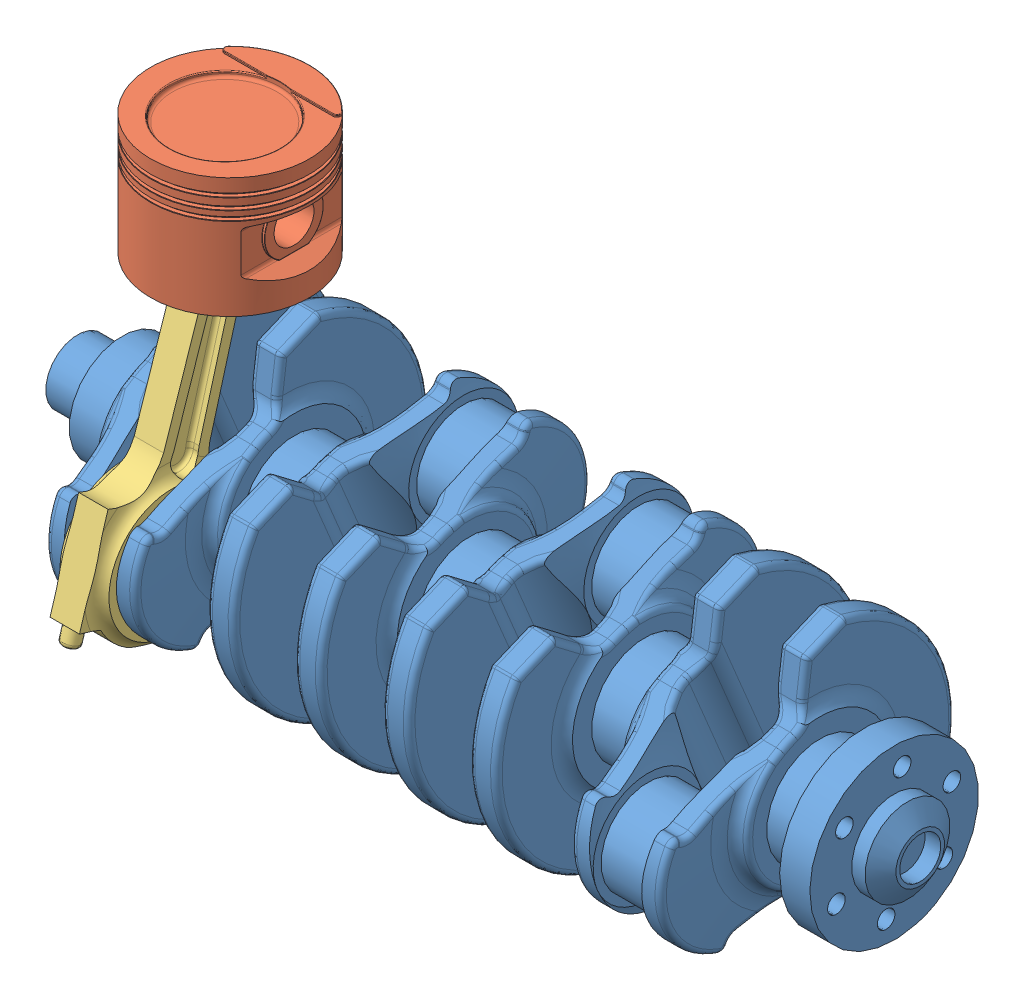
SolidWorks assembly Engine, configuration Default. Lengths in mm.
Overall size (462.5 296.54 181.27).
4 component instances, 3 part files, 4 mates.
Components (placement in the parent):
- Crankshaft-1: Crankshaft [Default] at (-1.3622 0 0) x (1 0 0) z (0 0.922873 0.385104) size (429.6 147.6 117)
- piston_rod-1: piston_rod [Default] at (29.6993 121.1932 0) size (81 215.94 127.72) (flexible)
  - Piston-1: Piston [Default] at (1.4385 31.8218 0) size (81 62.3 81)
  - ConRod-1: ConRod [Default] at (12.4385 -0.1282 0) x (0 0.291501 0.956571) z (-1 0 0) size (72.5 196.5 26.37)
Mates (geometry in assembly coordinates):
- Concentrico1: concentric aligned: cylinder of Crankshaft-1 through (-46.5622 0 0) axis (1 0 0) radius 16.3; line of assembly
- Concentrico2: concentric aligned: cylinder of Crankshaft-1 through (111.8201 -17.6378 42.2676) axis (-1 0 0) radius 24; cylinder of piston_rod-1/ConRod-1 through (41.6378 -17.6378 42.2676) axis (-1 0 0) radius 24
- Coincidente2: coincident anti-aligned: plane of Crankshaft-1 through (18.6378 0 0) normal (1 0 0); plane of piston_rod-1/ConRod-1 through (18.6378 -17.6378 42.2676) normal (-1 0 0)
- Concentrico3: concentric aligned: cylinder of piston_rod-1/Piston-1 through (31.1378 91.715 0) axis (0 1 0) radius 40.5; line of assembly
